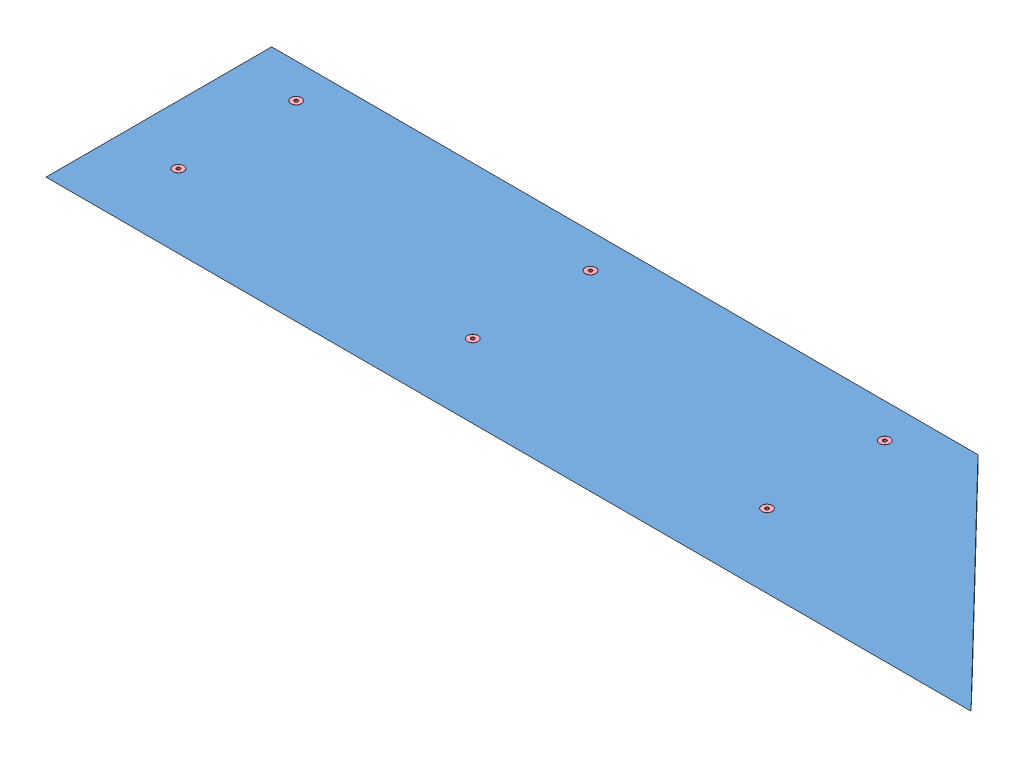
SolidWorks assembly GE-19058, configuration Default. Lengths in mm.
Overall size (1197.46 51.01 298.45).
16 component instances, 4 part files, 30 mates.
Components (placement in the parent):
- GE-19059-1: GE-19059 [Default] at (-11.9112 -4.3385 -141.1312) size (1197.46 12.7 292.1)
- GE-19055-1: GE-19055 [Default] at (-415.1362 -42.4385 -142.706) size (44.45 38.1 228.6)
- GE-19055-2: GE-19055 [Default] at (-34.1362 -42.4385 -142.706) size (44.45 38.1 228.6)
- GE-19055-3: GE-19055 [Default] at (346.8638 -42.4385 -142.706) size (44.45 38.1 228.6)
- nylock_.25_20-1: nylock_.25_20 [Default] at (369.0888 -9.1137 -96.6812) x (-0.837169 0 -0.546944) z (-0.546944 0 0.837169) size (11.11 7.94 12.83)
- nylock_.25_20-2: nylock_.25_20 [Default] at (369.0888 -9.1137 55.7188) x (-0.925243 0 -0.379375) z (-0.379375 0 0.925243) size (11.11 7.94 12.83)
- nylock_.25_20-4: nylock_.25_20 [Default] at (-11.9112 -9.1137 -96.6812) x (-0.997902 0 0.064746) z (0.064746 0 0.997902) size (11.11 7.94 12.83)
- nylock_.25_20-5: nylock_.25_20 [Default] at (-11.9112 -9.1137 55.7188) x (-0.953572 0 0.301166) z (0.301166 0 0.953572) size (11.11 7.94 12.83)
- nylock_.25_20-6: nylock_.25_20 [Default] at (-392.9112 -9.1137 -96.6812) x (-0.86157 0 0.507639) z (0.507639 0 0.86157) size (11.11 7.94 12.83)
- nylock_.25_20-7: nylock_.25_20 [Default] at (-392.9112 -9.1137 55.7188) x (-0.748019 0 0.663677) z (0.663677 0 0.748019) size (11.11 7.94 12.83)
- flat_hex_.25_20_1-1: flat_hex_.25_20_1 [91253A542] at (369.0888 8.3615 -96.6812) x (1 0 0) z (0 1 0) size (13.49 13.49 25.61)
- flat_hex_.25_20_1-2: flat_hex_.25_20_1 [91253A542] at (369.0888 8.3615 55.7188) x (0.982082 0 -0.188455) z (0 1 0) size (13.49 13.49 25.61)
- flat_hex_.25_20_1-3: flat_hex_.25_20_1 [91253A542] at (-11.9112 8.3615 55.7188) x (0.918365 0 -0.395734) z (0 1 0) size (13.49 13.49 25.61)
- flat_hex_.25_20_1-4: flat_hex_.25_20_1 [91253A542] at (-11.9112 8.3615 -96.6812) x (0.8 0 -0.6) z (0 1 0) size (13.49 13.49 25.61)
- flat_hex_.25_20_1-5: flat_hex_.25_20_1 [91253A542] at (-392.9112 8.3615 -96.6812) x (0.63358 0 -0.773678) z (0 1 0) size (13.49 13.49 25.61)
- flat_hex_.25_20_1-6: flat_hex_.25_20_1 [91253A542] at (-392.9112 8.3615 55.7188) x (0.443629 0 -0.896211) z (0 1 0) size (13.49 13.49 25.61)
Mates (geometry in assembly coordinates):
- Coincident1: coincident: plane of GE-19059-1 through (-11.9112 -4.3385 -141.1312) normal (0 -1 0); plane of GE-19055-1 through (-370.6862 -4.3385 81.1188) normal (0 1 0)
- Concentric1: concentric: cylinder of GE-19059-1 through (-392.9112 8.3615 -96.6812) axis (0 1 0) radius 3.5712; cylinder of GE-19055-1 through (-392.9112 -42.4385 -96.6812) axis (0 1 0) radius 3.3655
- Coincident2: coincident: plane of GE-19059-1 through (-11.9112 -4.3385 -141.1312) normal (0 -1 0); plane of GE-19055-2 through (10.3138 -4.3385 81.1188) normal (0 1 0)
- Concentric2: concentric: cylinder of GE-19059-1 through (-11.9112 8.3615 -96.6812) axis (0 1 0) radius 3.5712; cylinder of GE-19055-2 through (-11.9112 -42.4385 -96.6812) axis (0 1 0) radius 3.3655
- Coincident3: coincident: plane of GE-19059-1 through (-11.9112 -4.3385 -141.1312) normal (0 -1 0); plane of GE-19055-3 through (391.3138 -4.3385 81.1188) normal (0 1 0)
- Concentric3: concentric: cylinder of GE-19059-1 through (369.0888 8.3615 -96.6812) axis (0 1 0) radius 3.5712; cylinder of GE-19055-3 through (369.0888 -42.4385 -96.6812) axis (0 1 0) radius 3.3655
- Concentric4: concentric: cylinder of assembly; cylinder of assembly; cylinder of GE-19055-3 through (369.0888 -42.4385 -96.6812) axis (0 1 0) radius 3.3655; cylinder of nylock_.25_20-1 through (369.0888 -9.1137 -96.6812) axis (0 -1 0) radius 3.175
- Coincident4: coincident: plane of assembly; plane of assembly; plane of GE-19055-3 through (391.3138 -9.1137 -142.706) normal (0 -1 0); plane of nylock_.25_20-1 through (369.0888 -9.1137 -96.6812) normal (0 1 0)
- Coincident5: coincident: plane of assembly; plane of assembly; plane of GE-19055-3 through (391.3138 -9.1137 -142.706) normal (0 -1 0); plane of nylock_.25_20-2 through (369.0888 -9.1137 55.7188) normal (0 1 0)
- Concentric5: concentric: cylinder of assembly; cylinder of assembly; cylinder of GE-19055-3 through (369.0888 -42.4385 55.7188) axis (0 1 0) radius 3.3655; cylinder of nylock_.25_20-2 through (369.0888 -9.1137 55.7188) axis (0 -1 0) radius 3.175
- Coincident7: coincident: plane of assembly; plane of assembly; plane of GE-19055-3 through (391.3138 -9.1137 -142.706) normal (0 -1 0); plane of nylock_.25_20-4 through (-11.9112 -9.1137 -96.6812) normal (0 1 0)
- Concentric6: concentric: cylinder of assembly; cylinder of assembly; cylinder of GE-19055-2 through (-11.9112 -42.4385 -96.6812) axis (0 1 0) radius 3.3655; cylinder of nylock_.25_20-4 through (-11.9112 -9.1137 -96.6812) axis (0 -1 0) radius 3.175
- Coincident8: coincident: plane of assembly; plane of assembly; plane of GE-19055-3 through (391.3138 -9.1137 -142.706) normal (0 -1 0); plane of nylock_.25_20-5 through (-11.9112 -9.1137 55.7188) normal (0 1 0)
- Concentric7: concentric: cylinder of assembly; cylinder of assembly; cylinder of GE-19055-2 through (-11.9112 -42.4385 55.7188) axis (0 1 0) radius 3.3655; cylinder of nylock_.25_20-5 through (-11.9112 -9.1137 55.7188) axis (0 -1 0) radius 3.175
- Coincident9: coincident: plane of assembly; plane of assembly; plane of GE-19055-3 through (391.3138 -9.1137 -142.706) normal (0 -1 0); plane of nylock_.25_20-6 through (-392.9112 -9.1137 -96.6812) normal (0 1 0)
- Concentric8: concentric: cylinder of assembly; cylinder of assembly; cylinder of GE-19055-1 through (-392.9112 -42.4385 -96.6812) axis (0 1 0) radius 3.3655; cylinder of nylock_.25_20-6 through (-392.9112 -9.1137 -96.6812) axis (0 -1 0) radius 3.175
- Coincident10: coincident: plane of assembly; plane of assembly; plane of GE-19055-3 through (391.3138 -9.1137 -142.706) normal (0 -1 0); plane of nylock_.25_20-7 through (-392.9112 -9.1137 55.7188) normal (0 1 0)
- Concentric9: concentric: cylinder of assembly; cylinder of assembly; cylinder of GE-19055-1 through (-392.9112 -42.4385 55.7188) axis (0 1 0) radius 3.3655; cylinder of nylock_.25_20-7 through (-392.9112 -9.1137 55.7188) axis (0 -1 0) radius 3.175
- Concentric10: concentric: cylinder of GE-19059-1 through (369.0888 8.3615 -96.6812) axis (0 1 0) radius 3.5712; cylinder of flat_hex_.25_20_1-1 through (369.0888 -17.0385 -96.6812) axis (0 -1 0) radius 3.175
- Coincident12: coincident: plane of GE-19059-1 through (-11.9112 8.3615 -141.1312) normal (0 1 0); plane of flat_hex_.25_20_1-1 through (369.0888 8.3615 -93.5062) normal (0 1 0)
- Coincident13: coincident: plane of GE-19059-1 through (-11.9112 8.3615 -141.1312) normal (0 1 0); plane of flat_hex_.25_20_1-2 through (369.6871 8.3615 58.8369) normal (0 1 0)
- Concentric11: concentric: cylinder of GE-19059-1 through (369.0888 8.3615 55.7188) axis (0 1 0) radius 3.5712; cylinder of flat_hex_.25_20_1-2 through (369.0888 -17.0385 55.7188) axis (0 -1 0) radius 3.175
- Coincident14: coincident: plane of GE-19059-1 through (-11.9112 8.3615 -141.1312) normal (0 1 0); plane of flat_hex_.25_20_1-3 through (-10.6548 8.3615 58.6346) normal (0 1 0)
- Concentric12: concentric: cylinder of GE-19059-1 through (-11.9112 8.3615 55.7188) axis (0 1 0) radius 3.5712; cylinder of flat_hex_.25_20_1-3 through (-11.9112 -17.0385 55.7188) axis (0 -1 0) radius 3.175
- Coincident15: coincident: plane of GE-19059-1 through (-11.9112 8.3615 -141.1312) normal (0 1 0); plane of flat_hex_.25_20_1-4 through (-10.0062 8.3615 -94.1412) normal (0 1 0)
- Concentric13: concentric: cylinder of GE-19059-1 through (-11.9112 8.3615 -96.6812) axis (0 1 0) radius 3.5712; cylinder of flat_hex_.25_20_1-4 through (-11.9112 -17.0385 -96.6812) axis (0 -1 0) radius 3.175
- Coincident16: coincident: plane of GE-19059-1 through (-11.9112 8.3615 -141.1312) normal (0 1 0); plane of flat_hex_.25_20_1-5 through (-390.4548 8.3615 -94.6696) normal (0 1 0)
- Concentric14: concentric: cylinder of GE-19059-1 through (-392.9112 8.3615 -96.6812) axis (0 1 0) radius 3.5712; cylinder of flat_hex_.25_20_1-5 through (-392.9112 -17.0385 -96.6812) axis (0 -1 0) radius 3.175
- Coincident17: coincident: plane of GE-19059-1 through (-11.9112 8.3615 -141.1312) normal (0 1 0); plane of flat_hex_.25_20_1-6 through (-390.0658 8.3615 57.1273) normal (0 1 0)
- Concentric15: concentric: cylinder of GE-19059-1 through (-392.9112 8.3615 55.7188) axis (0 1 0) radius 3.5712; cylinder of flat_hex_.25_20_1-6 through (-392.9112 -17.0385 55.7188) axis (0 -1 0) radius 3.175
